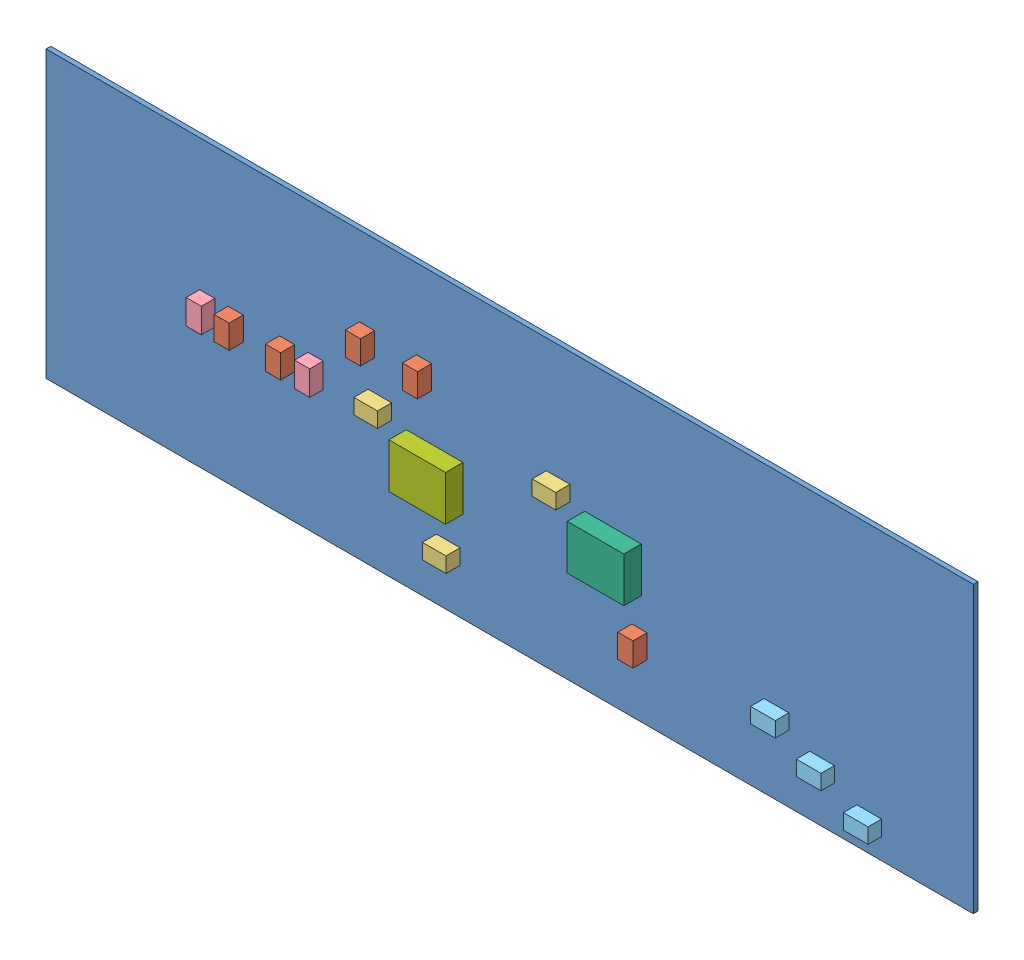
SolidWorks assembly sonar_DAQ_single, configuration Default. Lengths in mm.
Overall size (82.55 25.4 2.17).
46 component instances, 7 part files, 0 mates.
Components (placement in the parent):
- Board_1-1: Board_1 [Default] at (0 0 -0.4039) size (82.55 25.4 0.42)
- C1_1-1: C1_1 [Default] at origin size (1.35 2.1 1.26)
  - 407985696_1-1: 407985696_1 [Default] at (33.655 17.2596 0.0127) size (1.35 2.1 1.26)
    - Extruded_6-1: Extruded_6 [Default] at origin size (1.35 2.1 1.26)
- C2_1-1: C2_1 [Default] at origin size (2.1 1.35 1.26)
  - 407985824_1-1: 407985824_1 [Default] at (45.593 14.478 0.0127) size (2.1 1.35 1.26)
    - Extruded_7-1: Extruded_7 [Default] at origin size (2.1 1.35 1.26)
- C3_1-1: C3_1 [Default] at origin size (1.35 2.1 1.26)
  - 407985696_1-1: 407985696_1 [Default] at (52.832 6.096 0.0127) size (1.35 2.1 1.26)
    - Extruded_6-1: Extruded_6 [Default] at origin size (1.35 2.1 1.26)
- C4_1-1: C4_1 [Default] at origin size (2.1 1.35 1.26)
  - 407985824_1-1: 407985824_1 [Default] at (29.718 12.827 0.0127) size (2.1 1.35 1.26)
    - Extruded_7-1: Extruded_7 [Default] at origin size (2.1 1.35 1.26)
- C5_1-1: C5_1 [Default] at origin size (2.1 1.35 1.26)
  - 407985824_1-1: 407985824_1 [Default] at (35.814 4.699 0.0127) size (2.1 1.35 1.26)
    - Extruded_7-1: Extruded_7 [Default] at origin size (2.1 1.35 1.26)
- C6_1-1: C6_1 [Default] at origin size (1.35 2.2 1.2)
  - 407985568_1-1: 407985568_1 [Default] at (24.003 12.573 0.0127) size (1.35 2.2 1.2)
    - Extruded_8-1: Extruded_8 [Default] at origin size (1.35 2.2 1.2)
- C7_1-1: C7_1 [Default] at origin size (1.35 2.1 1.26)
  - 407985696_1-1: 407985696_1 [Default] at (21.463 12.623 0.0127) size (1.35 2.1 1.26)
    - Extruded_6-1: Extruded_6 [Default] at origin size (1.35 2.1 1.26)
- C8_1-1: C8_1 [Default] at origin size (1.35 2.1 1.26)
  - 407985696_1-1: 407985696_1 [Default] at (16.891 12.623 0.0127) size (1.35 2.1 1.26)
    - Extruded_6-1: Extruded_6 [Default] at origin size (1.35 2.1 1.26)
- C9_1-1: C9_1 [Default] at origin size (1.35 2.2 1.2)
  - 407985568_1-1: 407985568_1 [Default] at (14.351 12.573 0.0127) size (1.35 2.2 1.2)
    - Extruded_8-1: Extruded_8 [Default] at origin size (1.35 2.2 1.2)
- CL-1: CL [Default] at origin size (1.35 2.1 1.26)
  - 407985696_1-1: 407985696_1 [Default] at (28.575 17.2596 0.0127) size (1.35 2.1 1.26)
    - Extruded_6-1: Extruded_6 [Default] at origin size (1.35 2.1 1.26)
- CP1_1-1: CP1_1 [Default] at origin size (2.2 1.35 1.2)
  - 407988128-1: 407988128 [Default] at (65.024 6.604 0.0127) size (2.2 1.35 1.2)
    - Extruded_9-1: Extruded_9 [Default] at origin size (2.2 1.35 1.2)
- CP2_1-1: CP2_1 [Default] at origin size (2.2 1.35 1.2)
  - 407988128-1: 407988128 [Default] at (69.088 4.572 0.0127) size (2.2 1.35 1.2)
    - Extruded_9-1: Extruded_9 [Default] at origin size (2.2 1.35 1.2)
- CP3_1-1: CP3_1 [Default] at origin size (2.2 1.35 1.2)
  - 407988128-1: 407988128 [Default] at (73.279 2.54 0.0127) size (2.2 1.35 1.2)
    - Extruded_9-1: Extruded_9 [Default] at origin size (2.2 1.35 1.2)
- OP1_1-1: OP1_1 [Default] at origin size (5.04 3.99 1.55)
  - 407988256-1: 407988256 [Default] at (50.673 11.938 0.2157) size (5.04 3.99 1.55)
    - Extruded_10-1: Extruded_10 [Default] at origin size (5.04 3.99 1.55)
- OP2_1-1: OP2_1 [Default] at origin size (5.04 3.99 1.55)
  - 407985952_1-1: 407985952_1 [Default] at (34.798 10.287 0.2157) size (5.04 3.99 1.55)
    - Extruded_11-1: Extruded_11 [Default] at origin size (5.04 3.99 1.55)
